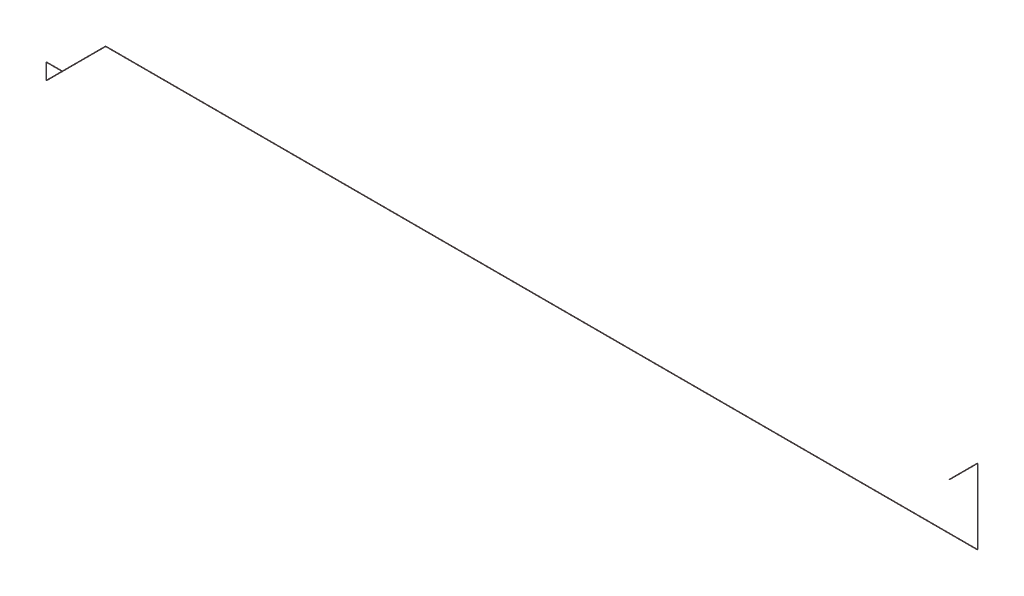
SolidWorks assembly Pipe3-SKLOP DISPOZICIJE, configuration Default. Lengths in mm.
Overall size (57197.42 4958.57 3932.42).
11 component instances, 2 part files, 0 mates.
Components (placement in the parent):
- 90deg LR Inch Elbow-1: 90deg LR Inch Elbow [90L LR Inch 1 Sch40] at (-17040.6015 9524.05 -32480.9) x (0 0 1) z (-1 0 0) size (64.95 64.95 33.73)
- 90deg LR Inch Elbow-2: 90deg LR Inch Elbow [90L LR Inch 1 Sch40] at (-17078.7015 4689.1 -32519) x (0 1 0) z (0 0 -1) size (64.95 64.95 33.73)
- 90deg LR Inch Elbow-3: 90deg LR Inch Elbow [90L LR Inch 1 Sch40] at (-74152.5015 4651 -32480.9) x (1 0 0) z (0 1 0) size (64.95 64.95 33.73)
- 90deg LR Inch Elbow-4: 90deg LR Inch Elbow [90L LR Inch 1 Sch40] at (-74190.6015 4689.1 -28672.1) x (0 0 -1) z (-1 0 0) size (64.95 64.95 33.73)
- 90deg LR Inch Elbow-5: 90deg LR Inch Elbow [90L LR Inch 1 Sch40] at (-74152.5015 5659.7839 -28634) x (0 -1 0) z (0 0 -1) size (64.95 64.95 33.73)
- 1inSchedule40-Pipe3-SKLOP DISPOZICIJE^Pipe3-SKLOP DISPOZICIJE-1: 1inSchedule40-Pipe3-SKLOP DISPOZICIJE^Pipe3-SKLOP DISPOZICIJE [1 in, Schedule 40] at (-17040.6015 9562.15 -30669) x (0.707107 0.707107 0) z (0 0 -1) size (33.53 33.53 1811.9) (virtual)
- 1inSchedule40-Pipe3-SKLOP DISPOZICIJE^Pipe3-SKLOP DISPOZICIJE-2: 1inSchedule40-Pipe3-SKLOP DISPOZICIJE^Pipe3-SKLOP DISPOZICIJE [1 in, Schedule 40, 1] at (-17040.6015 9524.05 -32519) x (0.707107 0 0.707107) z (0 -1 0) size (33.53 33.53 4834.95) (virtual)
- 1inSchedule40-Pipe3-SKLOP DISPOZICIJE^Pipe3-SKLOP DISPOZICIJE-3: 1inSchedule40-Pipe3-SKLOP DISPOZICIJE^Pipe3-SKLOP DISPOZICIJE [1 in, Schedule 40, 2] at (-17078.7015 4651 -32519) x (0 0.707107 0.707107) z (-1 0 0) size (33.53 33.53 57073.8) (virtual)
- 1inSchedule40-Pipe3-SKLOP DISPOZICIJE^Pipe3-SKLOP DISPOZICIJE-4: 1inSchedule40-Pipe3-SKLOP DISPOZICIJE^Pipe3-SKLOP DISPOZICIJE [1 in, Schedule 40, 3] at (-74190.6015 4651 -32480.9) x (0.707107 0.707107 0) z (0 0 1) size (33.53 33.53 3808.8) (virtual)
- 1inSchedule40-Pipe3-SKLOP DISPOZICIJE^Pipe3-SKLOP DISPOZICIJE-5: 1inSchedule40-Pipe3-SKLOP DISPOZICIJE^Pipe3-SKLOP DISPOZICIJE [1 in, Schedule 40, 4] at (-74190.6015 4689.1 -28634) x (0.707107 0 0.707107) z (0 1 0) size (33.53 33.53 970.68) (virtual)
- 1inSchedule40-Pipe3-SKLOP DISPOZICIJE^Pipe3-SKLOP DISPOZICIJE-6: 1inSchedule40-Pipe3-SKLOP DISPOZICIJE^Pipe3-SKLOP DISPOZICIJE [1 in, Schedule 40, 5] at (-74152.5015 5697.8839 -28634) x (0 0.707107 0.707107) z (1 0 0) size (33.53 33.53 972.4) (virtual)
